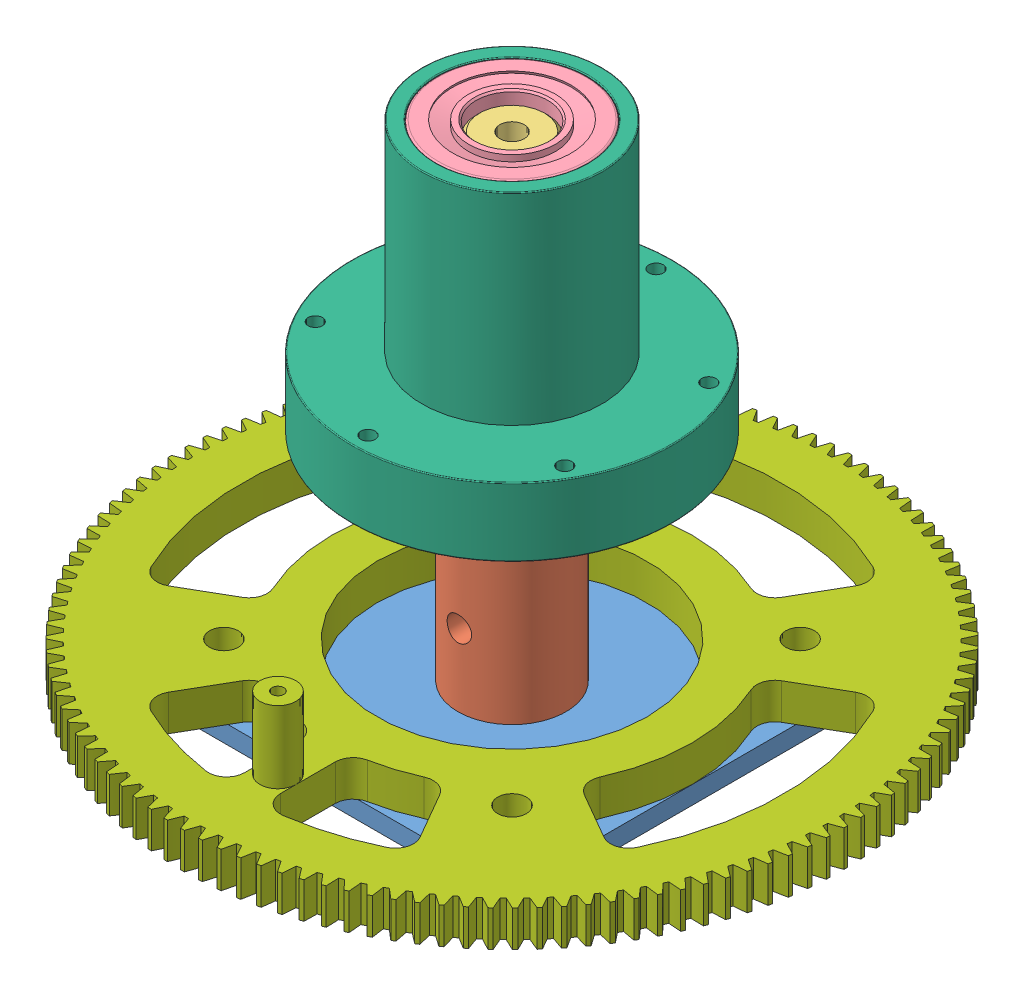
SolidWorks assembly Rotation_mechanism, configuration Default. Lengths in mm.
Overall size (182.99 140 182.98).
7 component instances, 6 part files, 14 mates.
Components (placement in the parent):
- Foot-1: Foot [Default] at origin size (100 5 100)
- Foot_bus-1: Foot_bus [Default] at (0 5 0) size (30 55 30)
- Main_axis-1: Main_axis [Default] at (0 10 0) size (24 127 24)
- taper roller bearing3_iso-1: taper roller bearing3_iso [ISO 355-3 - 3CC20 - 14,SI,NC,14] at (0 125 0) x (0 -1 0) z (-0.954411 0 -0.298495) size (15 42 42)
- taper roller bearing3_iso-2: taper roller bearing3_iso [ISO 355-3 - 3CC20 - 14,SI,NC,14] at (0 62 0) x (0 -1 0) z (0 0 1) size (15 42 42)
- Bearing_house_flange-1: Bearing_house_flange [Default] at (0 65 0) size (89 75 89)
- Spur_gear_big-1: Spur_gear_big [Default] at (0 15 0) x (1 0 0) z (0 1 0) size (182.99 182.98 30)
Mates (geometry in assembly coordinates):
- Coincident1: coincident: plane of Foot-1 through (0 5 0) normal (0 1 0); plane of Foot_bus-1 through (0 5 0) normal (0 -1 0)
- Coincident2: coincident: plane of Foot_bus-1 through (0 5 0) normal (1 0 0); plane of assembly through (0 0 0) normal (1 0 0)
- Coincident3: coincident: plane of Foot_bus-1 through (0 5 0) normal (0 0 1); plane of assembly through (0 0 0) normal (0 0 1)
- Concentric1: concentric: cylinder of Foot_bus-1 through (0 60 0) axis (0 -1 0) radius 10; cylinder of Main_axis-1 through (0 10 0) axis (0 -1 0) radius 9.95
- Coincident4: coincident: plane of Foot_bus-1 through (0 60 0) normal (0 1 0); plane of Main_axis-1 through (0 60 12) normal (0 -1 0)
- Concentric2: concentric: cylinder of Main_axis-1 through (0 10 0) axis (0 -1 0) radius 10; cylinder of taper roller bearing3_iso-1 through (0 167.5 0) axis (0 -1 0) radius 10
- Concentric31: concentric: cylinder of Main_axis-1 through (0 10 0) axis (0 -1 0) radius 10; cylinder of taper roller bearing3_iso-2 through (0 104.5 0) axis (0 -1 0) radius 14.9276
- Coincident51: coincident: plane of Main_axis-1 through (0 62 10) normal (0 1 0); plane of taper roller bearing3_iso-2 through (10.6 62 0) normal (0 -1 0)
- Coincident6: coincident: plane of taper roller bearing3_iso-2 through (16.3905 77 0) normal (0 1 0); plane of Bearing_house_flange-1 through (0 77 -21) normal (0 -1 0)
- Concentric4: concentric: cylinder of taper roller bearing3_iso-2 through (0 104.5 0) axis (0 -1 0) radius 21; cylinder of Bearing_house_flange-1 through (0 -935.2373 0) axis (0 -1 0) radius 21
- Coincident8: coincident: plane of taper roller bearing3_iso-1 through (-6.1251 128 19.5845) normal (0 -1 0); plane of Bearing_house_flange-1 through (0 128 -18.5) normal (0 1 0)
- Concentric5: concentric: cylinder of Foot_bus-1 through (0 60 0) axis (0 -1 0) radius 15; cylinder of Spur_gear_big-1 through (0 5 0) axis (0 1 0) radius 37.5
- Concentric6: concentric: cylinder of Foot-1 through (40 5 -40) axis (0 1 0) radius 4; cylinder of Spur_gear_big-1 through (40 5 -40) axis (0 1 0) radius 4
- Concentric7: concentric: cylinder of Foot-1 through (-40 5 40) axis (0 1 0) radius 4; cylinder of Spur_gear_big-1 through (-40 5 40) axis (0 1 0) radius 4
